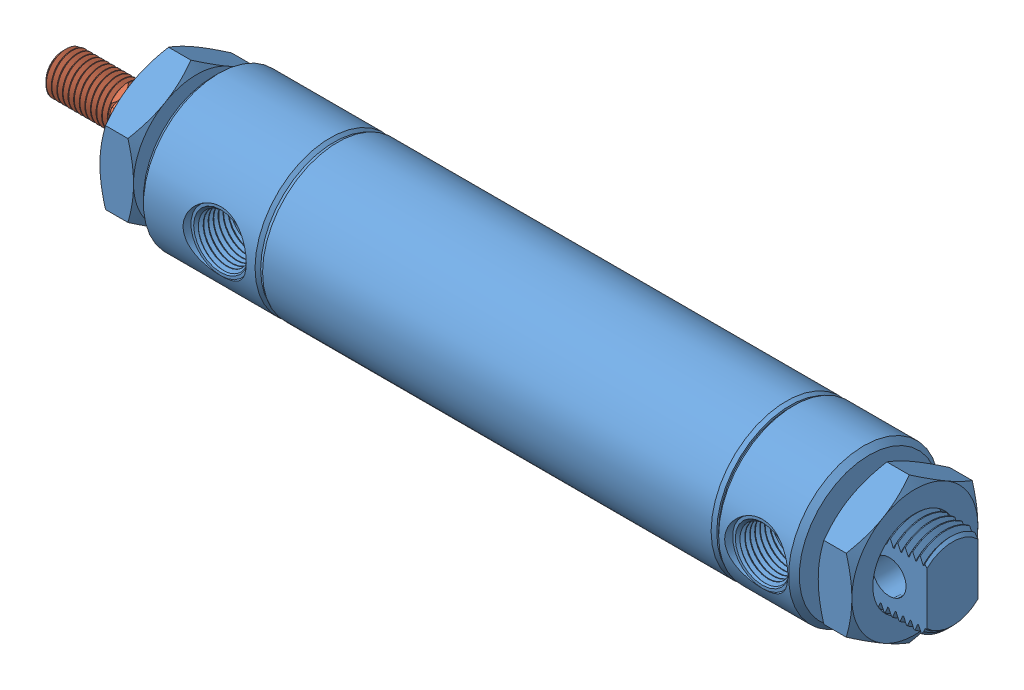
SolidWorks assembly Assem1, configuration Default. Lengths in mm.
Overall size (168.77 28.45 28.45).
2 component instances, 2 part files, 2 mates.
Components (placement in the parent):
- piston body-1: piston body [6498K654] at (48.3607 91.1672 114.2196) size (153.11 28.45 28.45)
- CYLINDER-1: CYLINDER [6498K654] at (48.3607 91.1672 114.2196) x (1 0 0) z (0 0.390257 -0.920706) size (70.22 8.18 8.17)
Mates (geometry in assembly coordinates):
- Concentric1: concentric: circle of piston body-1; cylinder of CYLINDER-1 through (-23.0133 91.1672 114.2196) axis (-1 0 0) radius 3.9624
- LimitDistance1: limit distance = 15.748 mm: plane of piston body-1 through (-19.9653 91.1672 114.2196) normal (-1 0 0); plane of CYLINDER-1 through (-35.7133 94.8213 115.7684) normal (-1 0 0)
